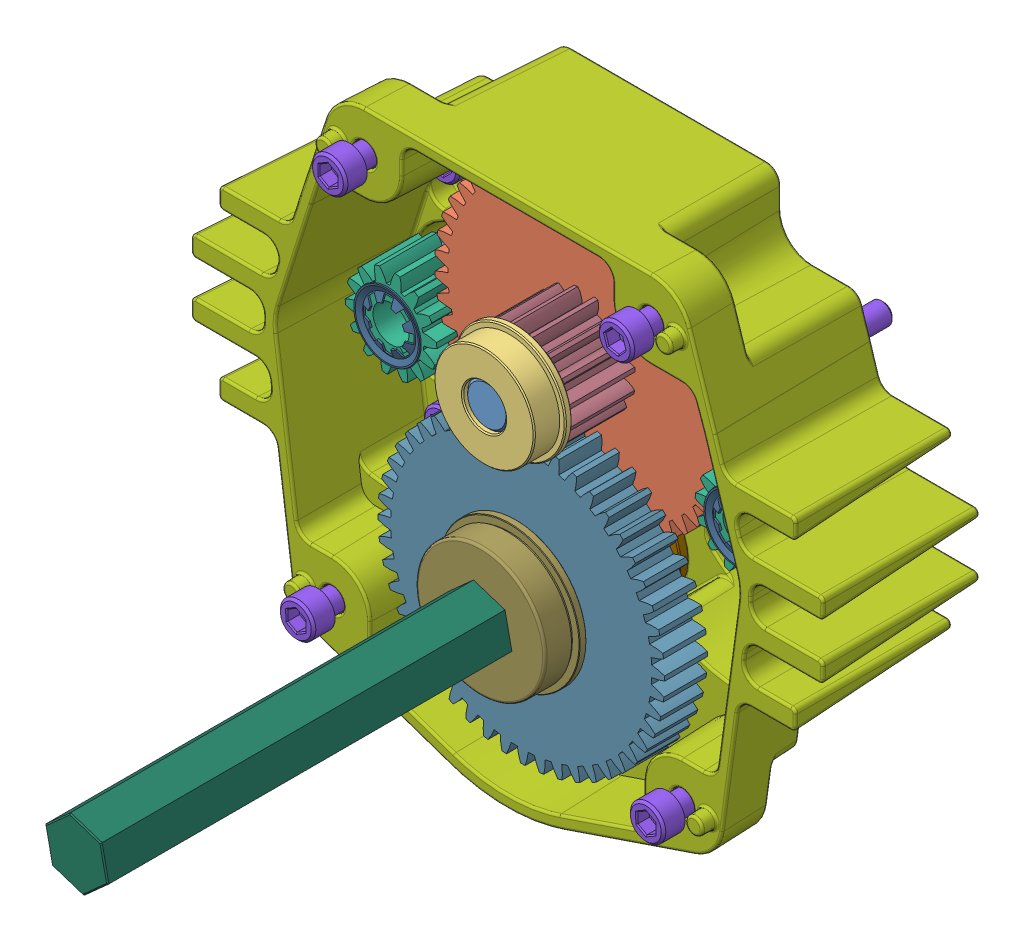
SolidWorks assembly Toughbox Mini Kit 1 - Yellow, configuration Default. Lengths in mm.
Overall size (140.05 131.97 142.29).
31 component instances, 15 part files, 74 mates.
Components (placement in the parent):
- TB Mini Small Hex Shaft-1: TB Mini Small Hex Shaft [Default] at (-128.9299 31.4042 -52.3959) x (-0.63944 -0.768841 0) z (-0.768841 0.63944 0) size (11 38.23 9.52)
- Large Cluster Gear Hex 50t 0.375 in-1: Large Cluster Gear Hex 50t 0.375 in [Default] at (-91.0349 50.9043 -67.5597) x (-0.63944 -0.768841 0) z (0 0 -1) size (65.97 66.04 10.16)
- Bearing FR6ZZ-1: Bearing FR6ZZ [Default] at (-96.247 60.278 -52.5991) x (-0.893862 0.448342 0) z (0 0 1) size (24.69 24.69 7.16)
- 10-32 Nylock Nut-1: 10-32 Nylock Nut [Default] at (-129.8464 -8.0737 -56.3837) x (0.501678 0.865055 0) z (0 0 -1) size (10.18 11.01 7.1)
- 10-32 Nylock Nut-2: 10-32 Nylock Nut [Default] at (-59.2462 80.7349 -56.3837) x (0.999999 -0.001296 0) z (0 0 -1) size (10.18 11.01 7.1)
- 10-32 Nylock Nut-3: 10-32 Nylock Nut [Default] at (-122.7461 80.8172 -56.3837) x (0.500567 0.865698 0) z (0 0 -1) size (10.18 11.01 7.1)
- 10-32 Nylock Nut-4: 10-32 Nylock Nut [Default] at (-52.3764 -8.1741 -56.3837) x (-0.501678 -0.865055 0) z (0 0 -1) size (10.18 11.01 7.1)
- Washer 5-16 in-1: Washer 5-16 in [Default] at (-52.3162 38.3079 -77.7705) x (-0.418041 0.908428 0) z (0 0 -1) size (17.53 17.53 1.47)
- Washer 5-16 in-2: Washer 5-16 in [Default] at (-52.3162 38.3079 -76.2973) x (0.897267 -0.441488 0) z (0 0 -1) size (17.53 17.53 1.47)
- Washer 5-16 in-3: Washer 5-16 in [Default] at (-129.7861 38.4083 -77.7705) x (-0.990116 0.140253 0) z (0 0 1) size (17.53 17.53 1.47)
- Washer 5-16 in-4: Washer 5-16 in [Default] at (-129.7861 38.4083 -79.2437) x (-0.681761 0.731575 0) z (0 0 1) size (17.53 17.53 1.47)
- CIM Gear 14t 8 mm-1: CIM Gear 14t 8 mm [Default] at (-52.3162 38.3079 -63.5973) x (0.081921 0.996639 0) z (0 0 -1) size (20.03 20.32 12.7)
- CIM Gear 14t 8 mm-2: CIM Gear 14t 8 mm [Default] at (-129.7861 38.4083 -63.5973) x (0.725998 0.687697 0) z (0 0 -1) size (20.03 20.32 12.7)
- TB Mini Housing-1: TB Mini Housing [Default] at (-91.0876 10.1882 -86.3557) x (0.999999 -0.001296 0) z (0 0 1) size (139.9 118.55 41.54)
- 10-32 x 0.625 in SHCS Screw-1: 10-32 x 0.625 in SHCS Screw [Default] at (-52.2832 63.7078 -74.4685) x (-0.564778 -0.825243 0) z (-0.825243 0.564778 0) size (7.82 20.65 7.82)
- 10-32 x 0.625 in SHCS Screw-2: 10-32 x 0.625 in SHCS Screw [Default] at (-122.7461 80.8172 -42.5915) x (0.507484 -0.861661 0) z (-0.861661 -0.507484 0) size (7.82 20.65 7.82)
- 10-32 x 0.625 in SHCS Screw-3: 10-32 x 0.625 in SHCS Screw [Default] at (-52.3764 -8.1741 -42.5915) x (0.507484 -0.861661 0) z (-0.861661 -0.507484 0) size (7.82 20.65 7.82)
- 10-32 x 0.625 in SHCS Screw-4: 10-32 x 0.625 in SHCS Screw [Default] at (-129.8464 -8.0737 -42.5915) x (0.507484 -0.861661 0) z (-0.861661 -0.507484 0) size (7.82 20.65 7.82)
- 10-32 x 0.625 in SHCS Screw-5: 10-32 x 0.625 in SHCS Screw [Default] at (-59.2462 80.7349 -42.5915) x (0.740711 -0.671824 0) z (-0.671824 -0.740711 0) size (7.82 20.65 7.82)
- 10-32 x 0.625 in SHCS Screw-6: 10-32 x 0.625 in SHCS Screw [Default] at (-52.3491 12.9079 -74.4685) x (-0.564778 -0.825243 0) z (-0.825243 0.564778 0) size (7.82 20.65 7.82)
- 10-32 x 0.625 in SHCS Screw-7: 10-32 x 0.625 in SHCS Screw [Default] at (-129.7532 63.8083 -74.4685) x (-0.966277 -0.257503 0) z (-0.257503 0.966277 0) size (7.82 20.65 7.82)
- 10-32 x 0.625 in SHCS Screw-8: 10-32 x 0.625 in SHCS Screw [Default] at (-129.819 13.0083 -74.4685) x (-0.99652 0.083357 0) z (0.083357 0.99652 0) size (7.82 20.65 7.82)
- Bearing R6ZZ-3: Bearing R6ZZ [Default] at (-91.0349 50.9043 -84.8317) x (0.958138 -0.286306 0) z (0 0 1) size (22.23 22.23 7.11)
- Bearing R6ZZ-4: Bearing R6ZZ [Default] at (-91.0876 10.1882 -84.8317) x (-0.661529 0.74992 0) z (0 0 1) size (22.23 22.23 7.11)
- Retaining Clip 8 mm-1: Retaining Clip 8 mm [Default] at (-129.7861 38.4083 -63.5973) x (0 0 1) z (-1 0 0) size (1.09 14.83 14.83)
- Retaining Clip 8 mm-2: Retaining Clip 8 mm [Default] at (-52.3162 38.3079 -63.5973) x (0 0 1) z (-1 0 0) size (1.09 14.83 14.83)
- External Klipring 0.5 in-1: External Klipring 0.5 in [Default] at (-91.0876 10.1882 -64.4355) x (0.996411 -0.084651 0) z (0 0 1) size (19.07 20.96 1.27)
- Hex Bearing FR8ZZ-1: Hex Bearing FR8ZZ [Default] at (-91.0876 10.1882 -44.6717) x (0.206517 -0.978443 0) z (0 0 -1) size (31.12 31.12 7.93)
- Small Cluster Gear Hex 16t 0.375 in-1: Small Cluster Gear Hex 16t 0.375 in [Default] at (-91.0349 50.9043 -67.5597) x (0 0 1) z (0.346116 -0.938192 0) size (15.19 22.57 22.57)
- Large Output Gear Hex 48t 0.5 in-1: Large Output Gear Hex 48t 0.5 in [Default] at (-91.0876 10.1882 -63.1655) x (0 0 1) z (0.744098 0.668071 0) size (10.21 63.42 63.42)
- TB Mini Hex Output Shaft-2: TB Mini Hex Output Shaft [Default] at (-99.4862 -30.7356 -52.3197) x (0.206517 -0.978443 0) z (-0.978443 -0.206517 0) size (14.66 142.29 12.7)
Mates (geometry in assembly coordinates):
- Concentric2: concentric aligned: circle of 10-32 Nylock Nut-3; circle of TB Mini Housing-1
- Coincident1: coincident anti-aligned: plane of 10-32 Nylock Nut-3 through (-122.7461 80.8172 -56.3837) normal (0 0 1); plane of TB Mini Housing-1 through (-132.6301 80.83 -56.3837) normal (0 0 -1)
- Parallel1: parallel: plane of 10-32 Nylock Nut-3 through (-125.1247 84.9432 -58.368) normal (-0.499433 0.866352 0); line of TB Mini Housing-1 through (-122.993 86.3757 -60.7105) axis (-0.866352 -0.499433 0)
- Concentric3: concentric anti-aligned: circle of 10-32 Nylock Nut-2; circle of TB Mini Housing-1
- Coincident3: coincident anti-aligned: plane of 10-32 Nylock Nut-2 through (-59.2462 80.7349 -56.3837) normal (0 0 1); plane of TB Mini Housing-1 through (-59.2388 86.4499 -56.3837) normal (0 0 -1)
- Parallel2: parallel: plane of 10-32 Nylock Nut-2 through (-54.4837 80.7287 -58.368) normal (0.999999 -0.001296 0); line of TB Mini Housing-1 through (-54.0512 78.1748 -60.9557) axis (0.001296 0.999999 0)
- Concentric4: concentric anti-aligned: circle of 10-32 Nylock Nut-4; circle of TB Mini Housing-1
- Coincident5: coincident anti-aligned: plane of 10-32 Nylock Nut-4 through (-52.3764 -8.1741 -56.3837) normal (0 0 1); plane of TB Mini Housing-1 through (-62.2604 -8.1613 -56.3837) normal (0 0 -1)
- Parallel3: parallel: plane of 10-32 Nylock Nut-4 through (-49.9872 -4.0543 -58.368) normal (0.501678 0.865055 0); line of TB Mini Housing-1 through (-47.5543 -4.9678 -60.9557) axis (-0.865055 0.501678 0)
- Concentric5: concentric aligned: circle of 10-32 Nylock Nut-1; circle of TB Mini Housing-1
- Coincident9: coincident anti-aligned: plane of 10-32 Nylock Nut-1 through (-129.8464 -8.0737 -56.3837) normal (0 0 1); plane of TB Mini Housing-1 through (-139.7304 -8.0609 -56.3837) normal (0 0 -1)
- Parallel4: parallel: plane of 10-32 Nylock Nut-1 through (-132.2356 -12.1935 -58.368) normal (-0.501678 -0.865055 0); line of TB Mini Housing-1 through (-130.235 -13.8511 -60.9557) axis (-0.865055 0.501678 0)
- Concentric6: concentric aligned: cylinder of TB Mini Housing-1 through (-129.7532 63.8083 -50.5417) axis (0 0 1) radius 2.5527; circle of 10-32 x 0.625 in SHCS Screw-7
- Coincident11: coincident anti-aligned: plane of TB Mini Housing-1 through (-59.2462 80.7349 -79.2437) normal (0 0 1); plane of 10-32 x 0.625 in SHCS Screw-7 through (-129.7532 63.8083 -79.2437) normal (0 0 -1)
- Concentric7: concentric anti-aligned: cylinder of TB Mini Housing-1 through (-52.2832 63.7078 -50.5417) axis (0 0 1) radius 2.5527; circle of 10-32 x 0.625 in SHCS Screw-1
- Coincident12: coincident anti-aligned: plane of TB Mini Housing-1 through (-59.2462 80.7349 -79.2437) normal (0 0 1); plane of 10-32 x 0.625 in SHCS Screw-1 through (-52.2832 63.7078 -79.2437) normal (0 0 -1)
- Concentric8: concentric aligned: cylinder of TB Mini Housing-1 through (-52.3491 12.9079 -50.5417) axis (0 0 1) radius 2.5527; cylinder of 10-32 x 0.625 in SHCS Screw-6 through (-52.3491 12.9079 -95.1187) axis (0 0 1) radius 2.3876
- Coincident13: coincident anti-aligned: plane of TB Mini Housing-1 through (-59.2462 80.7349 -79.2437) normal (0 0 1); plane of 10-32 x 0.625 in SHCS Screw-6 through (-52.3491 12.9079 -79.2437) normal (0 0 -1)
- Concentric9: concentric aligned: cylinder of TB Mini Housing-1 through (-129.819 13.0083 -50.5417) axis (0 0 1) radius 2.5527; cylinder of 10-32 x 0.625 in SHCS Screw-8 through (-129.819 13.0083 -95.1187) axis (0 0 1) radius 2.3876
- Coincident14: coincident anti-aligned: plane of TB Mini Housing-1 through (-59.2462 80.7349 -79.2437) normal (0 0 1); plane of 10-32 x 0.625 in SHCS Screw-8 through (-129.819 13.0083 -79.2437) normal (0 0 -1)
- Concentric12: concentric aligned: cylinder of Washer 5-16 in-3 through (-129.7861 38.4083 -76.2973) axis (0 0 -1) radius 8.763; cylinder of Washer 5-16 in-4 through (-129.7861 38.4083 -77.7705) axis (0 0 -1) radius 8.763
- Concentric13: concentric anti-aligned: circle of Washer 5-16 in-4; cylinder of TB Mini Housing-1 through (-129.7861 38.4083 -50.5417) axis (0 0 1) radius 10.414
- Coincident17: coincident anti-aligned: plane of Washer 5-16 in-4 through (-129.7861 38.4083 -79.2437) normal (0 0 -1); plane of TB Mini Housing-1 through (-59.2462 80.7349 -79.2437) normal (0 0 1)
- Coincident18: coincident anti-aligned: plane of Washer 5-16 in-3 through (-129.7861 38.4083 -77.7705) normal (0 0 -1); plane of Washer 5-16 in-4 through (-129.7861 38.4083 -77.7705) normal (0 0 1)
- Concentric14: concentric anti-aligned: circle of Washer 5-16 in-3; circle of CIM Gear 14t 8 mm-2
- Coincident19: coincident anti-aligned: plane of Washer 5-16 in-3 through (-129.7861 38.4083 -76.2973) normal (0 0 1); plane of CIM Gear 14t 8 mm-2 through (-129.7861 38.4083 -76.2973) normal (0 0 -1)
- Coincident21: coincident aligned: circle of Washer 5-16 in-1; circle of Washer 5-16 in-2
- Concentric16: concentric aligned: cylinder of Washer 5-16 in-1 through (-52.3162 38.3079 -79.2437) axis (0 0 1) radius 4.3942; cylinder of TB Mini Housing-1 through (-52.3162 38.3079 -50.5417) axis (0 0 1) radius 10.414
- Coincident22: coincident anti-aligned: plane of Washer 5-16 in-1 through (-52.3162 38.3079 -79.2437) normal (0 0 -1); plane of TB Mini Housing-1 through (-59.2462 80.7349 -79.2437) normal (0 0 1)
- Coincident23: coincident aligned: plane of Washer 5-16 in-2 through (-52.3162 38.3079 -76.2973) normal (0 0 1); circle of CIM Gear 14t 8 mm-1
- Concentric17: concentric aligned: circle of Washer 5-16 in-2; cylinder of CIM Gear 14t 8 mm-1 through (-52.3162 38.3079 -76.2973) axis (0 0 1) radius 4
- Parallel5: parallel anti-aligned: plane of TB Mini Small Hex Shaft-1 through (-96.4547 51.8356 -77.9229) normal (-0.938192 -0.346116 0); plane of Large Cluster Gear Hex 50t 0.375 in-1 through (-96.4547 51.8356 -67.5597) normal (0.938192 0.346116 0)
- Concentric20: concentric anti-aligned: circle of TB Mini Small Hex Shaft-1; circle of Large Cluster Gear Hex 50t 0.375 in-1
- Concentric27: concentric anti-aligned: cylinder of TB Mini Small Hex Shaft-1 through (-91.0349 50.9043 -46.0459) axis (0 0 -1) radius 4.7498; cylinder of Bearing FR6ZZ-1 through (-91.0349 50.9043 -51.0751) axis (0 0 1) radius 4.7625
- Coincident37: coincident aligned: plane of 10-32 x 0.625 in SHCS Screw-4 through (-129.8464 -8.0737 -47.3667) normal (0 0 -1); plane of 10-32 x 0.625 in SHCS Screw-5 through (-59.2462 80.7349 -47.3667) normal (0 0 -1)
- Coincident39: coincident aligned: plane of 10-32 x 0.625 in SHCS Screw-2 through (-122.7461 80.8172 -47.3667) normal (0 0 -1); plane of 10-32 x 0.625 in SHCS Screw-5 through (-59.2462 80.7349 -47.3667) normal (0 0 -1)
- Coincident40: coincident aligned: plane of 10-32 x 0.625 in SHCS Screw-2 through (-122.7461 80.8172 -47.3667) normal (0 0 -1); plane of 10-32 x 0.625 in SHCS Screw-3 through (-52.3764 -8.1741 -47.3667) normal (0 0 -1)
- Concentric34: concentric anti-aligned: cylinder of TB Mini Small Hex Shaft-1 through (-91.0349 50.9043 -84.2729) axis (0 0 1) radius 4.7498; cylinder of Bearing R6ZZ-3 through (-91.0349 50.9043 -77.7197) axis (0 0 -1) radius 11.1125
- Coincident49: coincident anti-aligned: plane of CIM Gear 14t 8 mm-2 through (-129.7861 38.4083 -63.5973) normal (0 0 1); circle of Retaining Clip 8 mm-1
- Concentric36: concentric aligned: circle of CIM Gear 14t 8 mm-2; circle of Retaining Clip 8 mm-1
- Coincident50: coincident anti-aligned: plane of CIM Gear 14t 8 mm-1 through (-52.3162 38.3079 -63.5973) normal (0 0 1); circle of Retaining Clip 8 mm-2
- Concentric37: concentric aligned: circle of CIM Gear 14t 8 mm-1; circle of Retaining Clip 8 mm-2
- Concentric48: concentric anti-aligned: cylinder of TB Mini Housing-1 through (-91.0876 10.1882 -50.5417) axis (0 0 1) radius 5.08; cylinder of Bearing R6ZZ-4 through (-91.0876 10.1882 -77.7197) axis (0 0 -1) radius 11.1125
- Coincident60: coincident anti-aligned: plane of TB Mini Housing-1 through (-91.0876 10.1882 -84.8317) normal (0 0 1); plane of Bearing R6ZZ-4 through (-91.0876 10.1882 -84.8317) normal (0 0 -1)
- Coincident62: coincident aligned: plane of Bearing FR6ZZ-1 through (-91.0349 50.9043 -51.0751) normal (0 0 1); plane of Hex Bearing FR8ZZ-1 through (-88.2026 -3.4807 -51.0751) normal (0 0 1)
- Coincident63: coincident anti-aligned: plane of TB Mini Housing-1 through (-91.0349 50.9043 -84.8317) normal (0 0 1); plane of Bearing R6ZZ-3 through (-91.0349 50.9043 -84.8317) normal (0 0 -1)
- Coincident64: coincident anti-aligned: plane of TB Mini Small Hex Shaft-1 through (-92.9382 56.0637 -77.7197) normal (0 0 -1); plane of Bearing R6ZZ-3 through (-91.0349 50.9043 -77.7197) normal (0 0 1)
- Coincident66: coincident anti-aligned: plane of Large Cluster Gear Hex 50t 0.375 in-1 through (-91.0349 50.9043 -77.7197) normal (0 0 -1); plane of Bearing R6ZZ-3 through (-91.0349 50.9043 -77.7197) normal (0 0 1)
- Coincident69: coincident anti-aligned: plane of TB Mini Small Hex Shaft-1 through (-87.5184 55.1324 -52.5991) normal (0 0 1); plane of Bearing FR6ZZ-1 through (-91.0349 50.9043 -52.5991) normal (0 0 -1)
- Concentric52: concentric aligned: cylinder of TB Mini Housing-1 through (-91.0349 50.9043 -84.8317) axis (0 0 -1) radius 11.1061; cylinder of Bearing R6ZZ-3 through (-91.0349 50.9043 -77.7197) axis (0 0 -1) radius 11.1125
- Distance1: distance = 3.175 mm anti-aligned: plane of TB Mini Housing-1 through (-91.0876 10.1882 -50.5417) normal (0 0 1); plane of 10-32 x 0.625 in SHCS Screw-5 through (-59.2462 80.7349 -47.3667) normal (0 0 -1)
- Concentric53: concentric aligned: cone of TB Mini Housing-1 through (-59.2462 80.7349 -55.8934) axis (0 0 1); cylinder of 10-32 x 0.625 in SHCS Screw-5 through (-59.2462 80.7349 -47.3667) axis (0 0 1) radius 3.9116
- Coincident71: coincident aligned: plane of 10-32 x 0.625 in SHCS Screw-2 through (-122.7461 80.8172 -42.5915) normal (0 0 1); plane of 10-32 x 0.625 in SHCS Screw-5 through (-59.2462 80.7349 -42.5915) normal (0 0 1)
- Concentric54: concentric aligned: cone of TB Mini Housing-1 through (-122.7461 80.8172 -55.8934) axis (0 0 1); cylinder of 10-32 x 0.625 in SHCS Screw-2 through (-122.7461 80.8172 -47.3667) axis (0 0 1) radius 3.9116
- Coincident72: coincident aligned: plane of 10-32 x 0.625 in SHCS Screw-3 through (-52.3764 -8.1741 -42.5915) normal (0 0 1); plane of 10-32 x 0.625 in SHCS Screw-5 through (-59.2462 80.7349 -42.5915) normal (0 0 1)
- Concentric55: concentric aligned: cone of TB Mini Housing-1 through (-52.3764 -8.1741 -55.8934) axis (0 0 1); cylinder of 10-32 x 0.625 in SHCS Screw-3 through (-52.3764 -8.1741 -47.3667) axis (0 0 1) radius 3.9116
- Coincident73: coincident aligned: plane of 10-32 x 0.625 in SHCS Screw-2 through (-122.7461 80.8172 -42.5915) normal (0 0 1); plane of 10-32 x 0.625 in SHCS Screw-4 through (-129.8464 -8.0737 -42.5915) normal (0 0 1)
- Concentric56: concentric aligned: cone of TB Mini Housing-1 through (-129.8464 -8.0737 -55.8934) axis (0 0 1); cylinder of 10-32 x 0.625 in SHCS Screw-4 through (-129.8464 -8.0737 -63.2417) axis (0 0 1) radius 2.3876
- Parallel6: parallel aligned: plane of TB Mini Small Hex Shaft-1 through (-96.4547 51.8356 -77.9229) normal (-0.938192 -0.346116 0); plane of Small Cluster Gear Hex 16t 0.375 in-1 through (-85.615 49.973 -67.5597) normal (-0.938192 -0.346116 0)
- Coincident75: coincident anti-aligned: plane of Large Cluster Gear Hex 50t 0.375 in-1 through (-91.0349 50.9043 -67.5597) normal (0 0 1); plane of Small Cluster Gear Hex 16t 0.375 in-1 through (-91.0349 50.9043 -67.5597) normal (0 0 -1)
- Concentric58: concentric anti-aligned: cylinder of Hex Bearing FR8ZZ-1 through (-91.0876 10.1882 -52.5991) axis (0 0 1) radius 14.2875; cylinder of Large Output Gear Hex 48t 0.5 in-1 through (-91.0876 10.1882 -52.9547) axis (0 0 -1) radius 8.89
- Coincident77: coincident anti-aligned: plane of External Klipring 0.5 in-1 through (-91.0876 10.1882 -63.1655) normal (0 0 1); plane of Large Output Gear Hex 48t 0.5 in-1 through (-91.0876 10.1882 -63.1655) normal (0 0 -1)
- Concentric59: concentric aligned: cylinder of Bearing FR6ZZ-1 through (-91.0349 50.9043 -45.4363) axis (0 0 1) radius 11.1125; circle of Small Cluster Gear Hex 16t 0.375 in-1
- Coincident80: coincident anti-aligned: plane of External Klipring 0.5 in-1 through (-91.0876 10.1882 -63.1655) normal (0 0 1); plane of Large Output Gear Hex 48t 0.5 in-1 through (-91.0876 10.1882 -63.1655) normal (0 0 -1)
- Concentric62: concentric anti-aligned: cylinder of Bearing R6ZZ-4 through (-91.0876 10.1882 -77.7197) axis (0 0 -1) radius 11.1125; cylinder of Hex Bearing FR8ZZ-1 through (-91.0876 10.1882 -52.5991) axis (0 0 1) radius 14.2875
- Concentric63: concentric anti-aligned: cylinder of Bearing R6ZZ-4 through (-91.0876 10.1882 -77.7197) axis (0 0 -1) radius 4.7625; cylinder of TB Mini Hex Output Shaft-2 through (-91.0876 10.1882 -84.8317) axis (0 0 1) radius 4.7498
- Coincident82: coincident anti-aligned: plane of Bearing R6ZZ-4 through (-91.0876 10.1882 -77.7197) normal (0 0 1); plane of TB Mini Hex Output Shaft-2 through (-103.5139 7.5654 -77.7197) normal (0 0 -1)
- Coincident83: coincident anti-aligned: plane of Hex Bearing FR8ZZ-1 through (-84.1174 7.9124 -52.5991) normal (-0.978443 -0.206517 0); plane of TB Mini Hex Output Shaft-2 through (-84.1174 7.9124 -77.7197) normal (0.978443 0.206517 0)
- Coincident84: coincident anti-aligned: plane of Large Output Gear Hex 48t 0.5 in-1 through (-84.8745 11.4995 -63.1655) normal (-0.978443 -0.206517 0); plane of TB Mini Hex Output Shaft-2 through (-84.1174 7.9124 -77.7197) normal (0.978443 0.206517 0)
- Concentric64: concentric anti-aligned: cylinder of External Klipring 0.5 in-1 through (-91.0876 10.1882 -63.1655) axis (0 0 -1) radius 5.1562; cylinder of TB Mini Hex Output Shaft-2 through (-91.0876 10.1882 -77.7197) axis (0 0 1) radius 5.588
- Coincident85: coincident anti-aligned: plane of External Klipring 0.5 in-1 through (-91.0876 10.1882 -64.4355) normal (0 0 -1); plane of TB Mini Hex Output Shaft-2 through (-87.6762 -5.9747 -64.4355) normal (0 0 1)
- GearMate1: gear = 1219.2 : 406.4 mm: circle of Small Cluster Gear Hex 16t 0.375 in-1; cylinder of Large Output Gear Hex 48t 0.5 in-1 through (-91.0876 10.1882 -52.9547) axis (0 0 -1) radius 8.89
- GearMate2: gear = 355.6 : 1270 mm: circle of Large Cluster Gear Hex 50t 0.375 in-1; cylinder of CIM Gear 14t 8 mm-2 through (-129.7861 38.4083 -76.2973) axis (0 0 1) radius 4
- GearMate3: gear = 355.6 : 1270 mm: circle of Large Cluster Gear Hex 50t 0.375 in-1; cylinder of CIM Gear 14t 8 mm-1 through (-52.3162 38.3079 -76.2973) axis (0 0 1) radius 4
